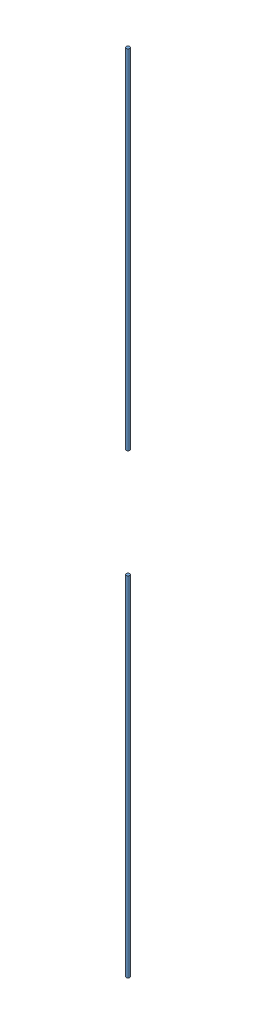
SolidWorks assembly 装配体1, configuration 默认. Lengths in mm.
Overall size (2.6 462.17 2.6).
2 component instances, 1 part files, 1 mates.
Components (placement in the parent):
- 绳-1: 绳 [默认] at (-76.9257 -91.8706 0) size (2 200 2)
- 绳-2: 绳 [默认] at (-76.9257 170.3032 0) x (-0.929351 0 0.369197) z (-0.369197 0 -0.929351) size (2 200 2)
Mates (geometry in assembly coordinates):
- 同心1: concentric aligned: cylinder of 绳-1 through (-76.9257 108.1294 0) axis (0 -1 0) radius 1; cylinder of 绳-2 through (-76.9257 370.3032 0) axis (0 -1 0) radius 1
